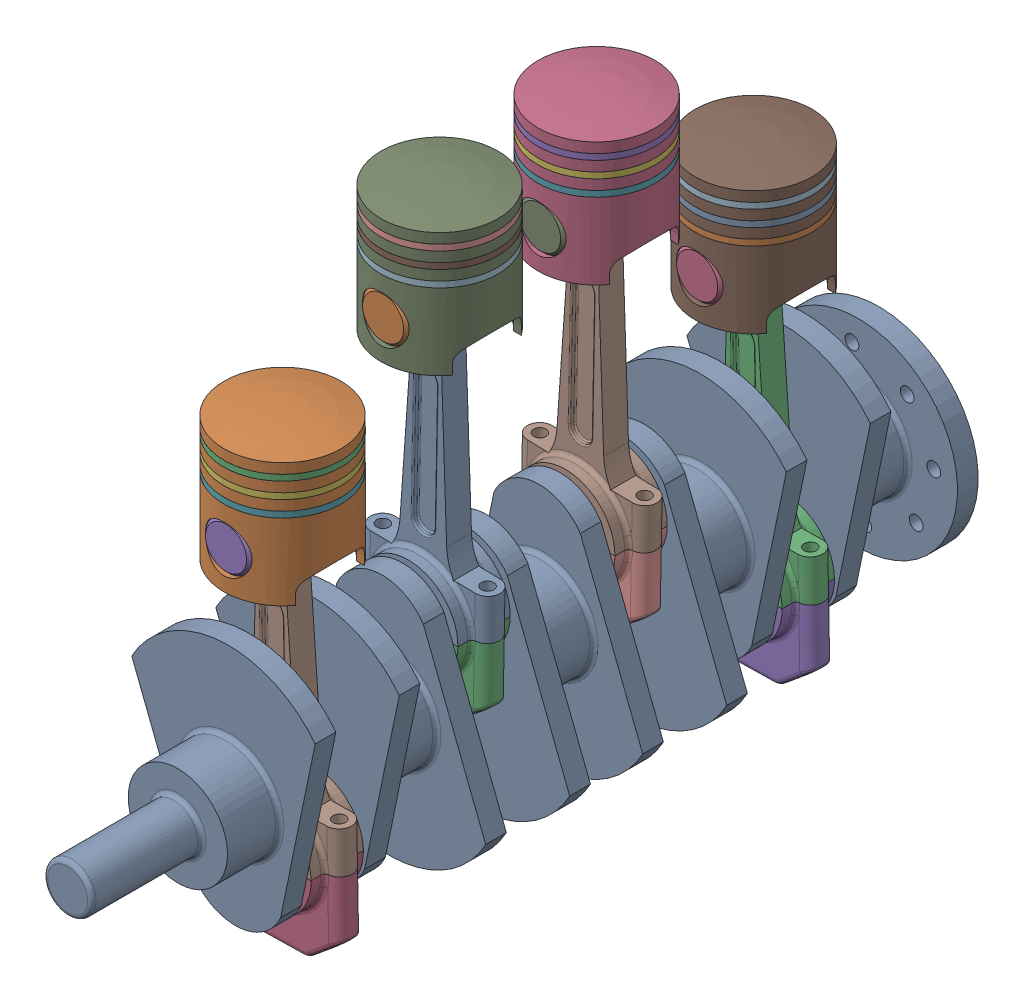
SolidWorks assembly FOUR CYLINDER ENGINE, configuration Default. Lengths in mm.
Overall size (159.32 417.71 589).
29 component instances, 6 part files, 66 mates.
Components (placement in the parent):
- 3.crankshaft-4: 3.crankshaft [Default] at (0 -6.9926 458.3563) x (0.996442 0.084279 0) z (0 0 1) size (144 187.9 589)
- 1.piston-1: 1.piston [Default] at (0 123.3298 435.3563) size (85 95 85)
- 2.piston ring-1: 2.piston ring [Default] at (0 201.7298 435.3563) size (85 4.3 85)
- 5.connecting rod cap-1: 5.connecting rod cap [Default] at (3.7083 -50.836 435.3563) x (-0.99983 -0.018431 0) z (0 0 1) size (94 60 38)
- 6.piston pin-1: 6.piston pin [Default] at (0 150.3298 435.3563) x (0.725621 -0.688095 0) z (0 0 1) size (33.8 33.8 82)
- 2.piston ring-2: 2.piston ring [Default] at (0 190.1298 435.3563) x (0.982082 0 -0.188455) z (0.188455 0 0.982082) size (85 4.3 85)
- 2.piston ring-3: 2.piston ring [Default] at (0 178.5298 435.3563) x (0.918365 0 -0.395734) z (0.395734 0 0.918365) size (85 4.3 85)
- 4.connecting rod-2: 4.connecting rod [Default] at (0 150.3298 435.3563) x (0.99983 0.018431 0) z (0 0 1) size (94 223.7 38)
- 1.piston-6: 1.piston [Default] at (0 211.0167 321.3563) size (85 95 85)
- 2.piston ring-16: 2.piston ring [Default] at (0 289.4167 321.3563) x (-0.972551 0 -0.23269) z (0.23269 0 -0.972551) size (85 4.3 85)
- 2.piston ring-17: 2.piston ring [Default] at (0 277.8167 321.3563) x (-0.998976 0 -0.045238) z (0.045238 0 -0.998976) size (85 4.3 85)
- 2.piston ring-18: 2.piston ring [Default] at (0 266.2167 321.3563) x (-0.98524 0 0.171178) z (-0.171178 0 -0.98524) size (85 4.3 85)
- 4.connecting rod-7: 4.connecting rod [Default] at (0 238.0167 321.3563) x (0.99983 -0.018431 0) z (0 0 1) size (94 223.7 38)
- 6.piston pin-6: 6.piston pin [Default] at (0 238.0167 321.3563) x (-0.514392 -0.857555 0) z (0 0 1) size (33.8 33.8 82)
- 5.connecting rod cap-6: 5.connecting rod cap [Default] at (-3.7083 36.8509 321.3563) x (-0.99983 0.018431 0) z (0 0 1) size (94 60 38)
- 1.piston-7: 1.piston [Default] at (0 211.0167 207.3563) x (-1 0 0) z (0 0 -1) size (85 95 85)
- 2.piston ring-19: 2.piston ring [Default] at (0 289.4167 207.3563) x (0.790546 0 -0.612403) z (0.612403 0 0.790546) size (85 4.3 85)
- 2.piston ring-20: 2.piston ring [Default] at (0 277.8167 207.3563) x (0.660971 0 -0.750412) z (0.750412 0 0.660971) size (85 4.3 85)
- 2.piston ring-21: 2.piston ring [Default] at (0 266.2167 207.3563) x (0.483661 0 -0.875255) z (0.875255 0 0.483661) size (85 4.3 85)
- 4.connecting rod-8: 4.connecting rod [Default] at (0 238.0167 207.3563) x (-0.99983 0.018431 0) z (0 0 -1) size (94 223.7 38)
- 6.piston pin-7: 6.piston pin [Default] at (0 238.0167 207.3563) x (-0.894775 0.446518 0) z (0 0 -1) size (33.8 33.8 82)
- 5.connecting rod cap-7: 5.connecting rod cap [Default] at (-3.7083 36.8509 207.3563) x (0.99983 -0.018431 0) z (0 0 -1) size (94 60 38)
- 1.piston-8: 1.piston [Default] at (0 123.3298 93.3563) x (-1 0 0) z (0 0 -1) size (85 95 85)
- 2.piston ring-22: 2.piston ring [Default] at (0 201.7298 93.3563) x (0.6 0 -0.8) z (0.8 0 0.6) size (85 4.3 85)
- 2.piston ring-23: 2.piston ring [Default] at (0 190.1298 93.3563) x (0.438485 0 -0.898738) z (0.898738 0 0.438485) size (85 4.3 85)
- 2.piston ring-24: 2.piston ring [Default] at (0 178.5298 93.3563) x (0.234432 0 -0.972133) z (0.972133 0 0.234432) size (85 4.3 85)
- 4.connecting rod-9: 4.connecting rod [Default] at (0 150.3298 93.3563) x (-0.99983 -0.018431 0) z (0 0 -1) size (94 223.7 38)
- 6.piston pin-8: 6.piston pin [Default] at (0 150.3298 93.3563) x (-0.958718 0.284359 0) z (0 0 -1) size (33.8 33.8 82)
- 5.connecting rod cap-8: 5.connecting rod cap [Default] at (3.7083 -50.836 93.3563) x (0.99983 0.018431 0) z (0 0 -1) size (94 60 38)
Mates (geometry in assembly coordinates):
- Concentric1: concentric anti-aligned: cylinder of 3.crankshaft-4 through (0 -6.9926 591.3563) axis (0 0 -1) radius 17.5
- Coincident1: coincident: plane of 3.crankshaft-4 through (0 -6.9926 591.3563) normal (0 0 1)
- Coincident2: coincident aligned: plane of 1.piston-1 through (0 123.264 435.3563) normal (0 0 1); plane of 6.piston pin-1 through (0 150.264 435.3563) normal (0 0 1)
- Concentric2: concentric anti-aligned: cylinder of 1.piston-1 through (0 150.264 392.8563) axis (0 0 1) radius 16.9; cylinder of 6.piston pin-1 through (0 150.264 476.3563) axis (0 0 -1) radius 16.9
- Concentric11: concentric anti-aligned: cylinder of 1.piston-1 through (0 201.664 435.3563) axis (0 1 0) radius 39.5; cylinder of 2.piston ring-1 through (0 205.964 435.3563) axis (0 -1 0) radius 42.5
- Coincident3: coincident anti-aligned: plane of 1.piston-1 through (0 201.664 435.3563) normal (0 1 0); plane of 2.piston ring-1 through (0 201.664 435.3563) normal (0 -1 0)
- Concentric12: concentric anti-aligned: cylinder of 1.piston-1 through (0 190.064 435.3563) axis (0 1 0) radius 39.5; cylinder of 2.piston ring-2 through (0 194.364 435.3563) axis (0 -1 0) radius 42.5
- Coincident4: coincident anti-aligned: plane of 1.piston-1 through (0 190.064 435.3563) normal (0 1 0); plane of 2.piston ring-2 through (0 190.064 435.3563) normal (0 -1 0)
- Concentric13: concentric anti-aligned: cylinder of 1.piston-1 through (0 178.464 435.3563) axis (0 1 0) radius 39.5; cylinder of 2.piston ring-3 through (0 182.764 435.3563) axis (0 -1 0) radius 42.5
- Coincident5: coincident anti-aligned: plane of 1.piston-1 through (0 178.464 435.3563) normal (0 1 0); plane of 2.piston ring-3 through (0 178.464 435.3563) normal (0 -1 0)
- Coincident6: coincident aligned: plane of 1.piston-1 through (0 123.264 435.3563) normal (0 0 1); plane of 4.connecting rod-2 through (0 150.264 435.3563) normal (0 0 1)
- Concentric14: concentric aligned: cylinder of 6.piston pin-1 through (0 150.264 476.3563) axis (0 0 -1) radius 16.9; cylinder of 4.connecting rod-2 through (0 150.264 454.3563) axis (0 0 -1) radius 16.9
- Concentric15: concentric aligned: cylinder of 5.connecting rod cap-1 through (34.7213 -111.392 435.3563) axis (0.012541 0.999921 0) radius 4.5; cylinder of 4.connecting rod-2 through (35.4737 -51.3967 435.3563) axis (0.012541 0.999921 0) radius 4.5
- Concentric16: concentric aligned: cylinder of 5.connecting rod cap-1 through (-41.2727 -110.4389 435.3563) axis (0.012541 0.999921 0) radius 4.5; cylinder of 4.connecting rod-2 through (-40.5203 -50.4436 435.3563) axis (0.012541 0.999921 0) radius 4.5
- Coincident7: coincident anti-aligned: plane of 5.connecting rod cap-1 through (33.4739 -51.3717 454.3563) normal (0.012541 0.999921 0); plane of 4.connecting rod-2 through (-2.5233 -50.9202 454.3563) normal (-0.012541 -0.999921 0)
- Width1: width anti-aligned: plane of 3.crankshaft-4 through (0 -6.9926 412.3563) normal (0 0 1); plane of 4.connecting rod-2 through (0 -6.9926 458.3563) normal (0 0 -1); plane of 3.crankshaft-4 through (0 150.264 426.3563) normal (0 0 -1); plane of 4.connecting rod-2 through (0 150.264 444.3563) normal (0 0 1)
- Concentric17: concentric anti-aligned: cylinder of 3.crankshaft-4 through (-2.5233 -50.9202 412.3563) axis (0 0 1) radius 27; cylinder of 5.connecting rod cap-1 through (-2.5233 -50.9202 454.3563) axis (0 0 -1) radius 27
- Concentric18: concentric anti-aligned: cylinder of 1.piston-1 through (0 213.264 435.3563) axis (0 -1 0) radius 42.5
- Coincident33: coincident aligned: plane of 1.piston-6 through (0 211.1192 321.3563) normal (0 0 1); plane of 6.piston pin-6 through (0 238.1192 321.3563) normal (0 0 1)
- Concentric55: concentric anti-aligned: cylinder of 1.piston-6 through (0 238.1192 278.8563) axis (0 0 1) radius 16.9; cylinder of 6.piston pin-6 through (0 238.1192 362.3563) axis (0 0 -1) radius 16.9
- Concentric56: concentric anti-aligned: cylinder of 1.piston-6 through (0 289.5192 321.3563) axis (0 1 0) radius 39.5; cylinder of 2.piston ring-16 through (0 293.8192 321.3563) axis (0 -1 0) radius 42.5
- Coincident34: coincident anti-aligned: plane of 1.piston-6 through (0 289.5192 321.3563) normal (0 1 0); plane of 2.piston ring-16 through (0 289.5192 321.3563) normal (0 -1 0)
- Concentric57: concentric anti-aligned: cylinder of 1.piston-6 through (0 277.9192 321.3563) axis (0 1 0) radius 39.5; cylinder of 2.piston ring-17 through (0 282.2192 321.3563) axis (0 -1 0) radius 42.5
- Coincident35: coincident anti-aligned: plane of 1.piston-6 through (0 277.9192 321.3563) normal (0 1 0); plane of 2.piston ring-17 through (0 277.9192 321.3563) normal (0 -1 0)
- Concentric58: concentric anti-aligned: cylinder of 1.piston-6 through (0 266.3192 321.3563) axis (0 1 0) radius 39.5; cylinder of 2.piston ring-18 through (0 270.6192 321.3563) axis (0 -1 0) radius 42.5
- Coincident36: coincident anti-aligned: plane of 1.piston-6 through (0 266.3192 321.3563) normal (0 1 0); plane of 2.piston ring-18 through (0 266.3192 321.3563) normal (0 -1 0)
- Coincident37: coincident aligned: plane of 1.piston-6 through (0 211.1192 321.3563) normal (0 0 1); plane of 4.connecting rod-7 through (0 238.1192 321.3563) normal (0 0 1)
- Concentric59: concentric aligned: cylinder of 4.connecting rod-7 through (0 238.1192 340.3563) axis (0 0 -1) radius 16.9; cylinder of 6.piston pin-6 through (0 238.1192 362.3563) axis (0 0 -1) radius 16.9
- Concentric60: concentric aligned: cylinder of 4.connecting rod-7 through (40.5203 37.4116 321.3563) axis (-0.012541 0.999921 0) radius 4.5; cylinder of 5.connecting rod cap-6 through (41.2727 -22.5837 321.3563) axis (-0.012541 0.999921 0) radius 4.5
- Concentric61: concentric aligned: cylinder of 4.connecting rod-7 through (-35.4737 36.4584 321.3563) axis (-0.012541 0.999921 0) radius 4.5; cylinder of 5.connecting rod cap-6 through (-34.7213 -23.5368 321.3563) axis (-0.012541 0.999921 0) radius 4.5
- Coincident38: coincident anti-aligned: plane of 4.connecting rod-7 through (2.5233 36.935 340.3563) normal (0.012541 -0.999921 0); plane of 5.connecting rod cap-6 through (38.5204 37.3865 340.3563) normal (-0.012541 0.999921 0)
- Width7: width anti-aligned: plane of 3.crankshaft-4 through (0 -6.9926 344.3563) normal (0 0 -1); plane of 4.connecting rod-7 through (0 -6.9926 298.3563) normal (0 0 1); plane of 3.crankshaft-4 through (0 238.1192 312.3563) normal (0 0 -1); plane of 4.connecting rod-7 through (0 238.1192 330.3563) normal (0 0 1)
- Concentric62: concentric anti-aligned: cylinder of 3.crankshaft-4 through (2.5233 36.935 298.3563) axis (0 0 1) radius 27; cylinder of 5.connecting rod cap-6 through (2.5233 36.935 340.3563) axis (0 0 -1) radius 27
- Concentric63: concentric aligned: cylinder of 1.piston-6 through (0 301.1192 321.3563) axis (0 -1 0) radius 42.5
- Coincident39: coincident aligned: plane of 1.piston-7 through (0 211.1192 207.3563) normal (0 0 -1); plane of 6.piston pin-7 through (0 238.1192 207.3563) normal (0 0 -1)
- Concentric64: concentric anti-aligned: cylinder of 1.piston-7 through (0 238.1192 249.8563) axis (0 0 -1) radius 16.9; cylinder of 6.piston pin-7 through (0 238.1192 166.3563) axis (0 0 1) radius 16.9
- Concentric65: concentric anti-aligned: cylinder of 1.piston-7 through (0 289.5192 207.3563) axis (0 1 0) radius 39.5; cylinder of 2.piston ring-19 through (0 293.8192 207.3563) axis (0 -1 0) radius 42.5
- Coincident40: coincident anti-aligned: plane of 1.piston-7 through (0 289.5192 207.3563) normal (0 1 0); plane of 2.piston ring-19 through (0 289.5192 207.3563) normal (0 -1 0)
- Concentric66: concentric anti-aligned: cylinder of 1.piston-7 through (0 277.9192 207.3563) axis (0 1 0) radius 39.5; cylinder of 2.piston ring-20 through (0 282.2192 207.3563) axis (0 -1 0) radius 42.5
- Coincident41: coincident anti-aligned: plane of 1.piston-7 through (0 277.9192 207.3563) normal (0 1 0); plane of 2.piston ring-20 through (0 277.9192 207.3563) normal (0 -1 0)
- Concentric67: concentric anti-aligned: cylinder of 1.piston-7 through (0 266.3192 207.3563) axis (0 1 0) radius 39.5; cylinder of 2.piston ring-21 through (0 270.6192 207.3563) axis (0 -1 0) radius 42.5
- Coincident42: coincident anti-aligned: plane of 1.piston-7 through (0 266.3192 207.3563) normal (0 1 0); plane of 2.piston ring-21 through (0 266.3192 207.3563) normal (0 -1 0)
- Coincident43: coincident aligned: plane of 1.piston-7 through (0 211.1192 207.3563) normal (0 0 -1); plane of 4.connecting rod-8 through (0 238.1192 207.3563) normal (0 0 -1)
- Concentric68: concentric aligned: cylinder of 4.connecting rod-8 through (0 238.1192 188.3563) axis (0 0 1) radius 16.9; cylinder of 6.piston pin-7 through (0 238.1192 166.3563) axis (0 0 1) radius 16.9
- Concentric69: concentric aligned: cylinder of 4.connecting rod-8 through (-35.4737 36.4584 207.3563) axis (-0.012541 0.999921 0) radius 4.5; cylinder of 5.connecting rod cap-7 through (-34.7213 -23.5368 207.3563) axis (-0.012541 0.999921 0) radius 4.5
- Concentric70: concentric aligned: cylinder of 4.connecting rod-8 through (40.5203 37.4116 207.3563) axis (-0.012541 0.999921 0) radius 4.5; cylinder of 5.connecting rod cap-7 through (41.2727 -22.5837 207.3563) axis (-0.012541 0.999921 0) radius 4.5
- Coincident44: coincident anti-aligned: plane of 4.connecting rod-8 through (2.5233 36.935 188.3563) normal (0.012541 -0.999921 0); plane of 5.connecting rod cap-7 through (-33.4739 36.4835 188.3563) normal (-0.012541 0.999921 0)
- Width8: width anti-aligned: plane of 3.crankshaft-4 through (0 -6.9926 230.3563) normal (0 0 -1); plane of 4.connecting rod-8 through (0 -6.9926 184.3563) normal (0 0 1); plane of 3.crankshaft-4 through (0 238.1192 216.3563) normal (0 0 1); plane of 4.connecting rod-8 through (0 238.1192 198.3563) normal (0 0 -1)
- Concentric71: concentric anti-aligned: cylinder of 3.crankshaft-4 through (2.5233 36.935 230.3563) axis (0 0 -1) radius 27; cylinder of 5.connecting rod cap-7 through (2.5233 36.935 188.3563) axis (0 0 1) radius 27
- Concentric72: concentric anti-aligned: cylinder of 1.piston-7 through (0 301.1192 207.3563) axis (0 -1 0) radius 42.5
- Coincident45: coincident aligned: plane of 1.piston-8 through (0 123.264 93.3563) normal (0 0 -1); plane of 6.piston pin-8 through (0 150.264 93.3563) normal (0 0 -1)
- Concentric73: concentric anti-aligned: cylinder of 1.piston-8 through (0 150.264 135.8563) axis (0 0 -1) radius 16.9; cylinder of 6.piston pin-8 through (0 150.264 52.3563) axis (0 0 1) radius 16.9
- Concentric74: concentric anti-aligned: cylinder of 1.piston-8 through (0 201.664 93.3563) axis (0 1 0) radius 39.5; cylinder of 2.piston ring-22 through (0 205.964 93.3563) axis (0 -1 0) radius 42.5
- Coincident46: coincident anti-aligned: plane of 1.piston-8 through (0 201.664 93.3563) normal (0 1 0); plane of 2.piston ring-22 through (0 201.664 93.3563) normal (0 -1 0)
- Concentric75: concentric anti-aligned: cylinder of 1.piston-8 through (0 190.064 93.3563) axis (0 1 0) radius 39.5; cylinder of 2.piston ring-23 through (0 194.364 93.3563) axis (0 -1 0) radius 42.5
- Coincident47: coincident anti-aligned: plane of 1.piston-8 through (0 190.064 93.3563) normal (0 1 0); plane of 2.piston ring-23 through (0 190.064 93.3563) normal (0 -1 0)
- Concentric76: concentric anti-aligned: cylinder of 1.piston-8 through (0 178.464 93.3563) axis (0 1 0) radius 39.5; cylinder of 2.piston ring-24 through (0 182.764 93.3563) axis (0 -1 0) radius 42.5
- Coincident48: coincident anti-aligned: plane of 1.piston-8 through (0 178.464 93.3563) normal (0 1 0); plane of 2.piston ring-24 through (0 178.464 93.3563) normal (0 -1 0)
- Coincident49: coincident aligned: plane of 1.piston-8 through (0 123.264 93.3563) normal (0 0 -1); plane of 4.connecting rod-9 through (0 150.264 93.3563) normal (0 0 -1)
- Concentric77: concentric aligned: cylinder of 4.connecting rod-9 through (0 150.264 74.3563) axis (0 0 1) radius 16.9; cylinder of 6.piston pin-8 through (0 150.264 52.3563) axis (0 0 1) radius 16.9
- Concentric78: concentric aligned: cylinder of 4.connecting rod-9 through (-40.5203 -50.4436 93.3563) axis (0.012541 0.999921 0) radius 4.5; cylinder of 5.connecting rod cap-8 through (-41.2727 -110.4389 93.3563) axis (0.012541 0.999921 0) radius 4.5
- Concentric79: concentric aligned: cylinder of 4.connecting rod-9 through (35.4737 -51.3967 93.3563) axis (0.012541 0.999921 0) radius 4.5; cylinder of 5.connecting rod cap-8 through (34.7213 -111.392 93.3563) axis (0.012541 0.999921 0) radius 4.5
- Coincident50: coincident anti-aligned: plane of 4.connecting rod-9 through (-2.5233 -50.9202 74.3563) normal (-0.012541 -0.999921 0); plane of 5.connecting rod cap-8 through (-38.5204 -50.4687 74.3563) normal (0.012541 0.999921 0)
- Width9: width anti-aligned: plane of 3.crankshaft-4 through (0 -6.9926 116.3563) normal (0 0 -1); plane of 4.connecting rod-9 through (0 -6.9926 70.3563) normal (0 0 1); plane of 3.crankshaft-4 through (0 150.264 102.3563) normal (0 0 1); plane of 4.connecting rod-9 through (0 150.264 84.3563) normal (0 0 -1)
- Concentric80: concentric anti-aligned: cylinder of 3.crankshaft-4 through (-2.5233 -50.9202 116.3563) axis (0 0 -1) radius 27; cylinder of 5.connecting rod cap-8 through (-2.5233 -50.9202 74.3563) axis (0 0 1) radius 27
- Concentric81: concentric anti-aligned: cylinder of 1.piston-8 through (0 213.264 93.3563) axis (0 -1 0) radius 42.5
